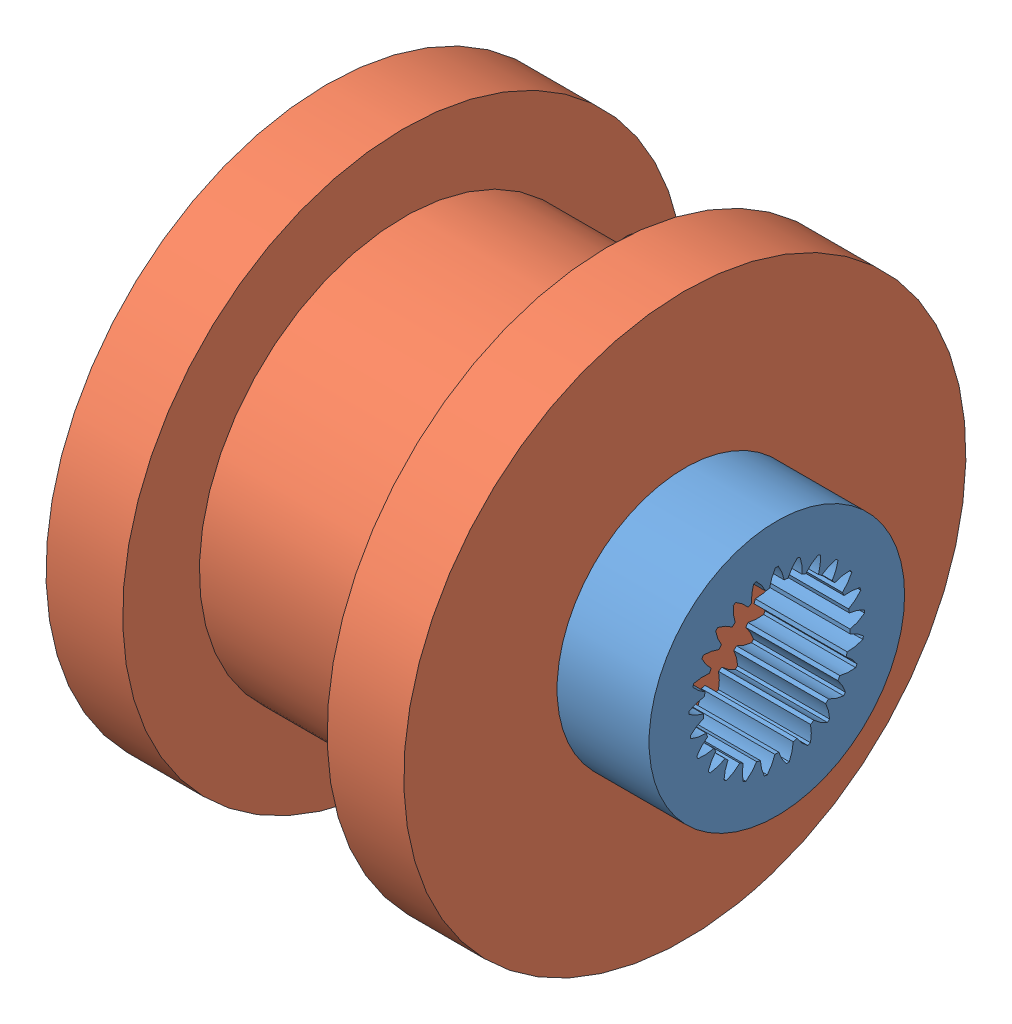
SolidWorks assembly Assem9, configuration Default. Lengths in mm.
Overall size (17.6 26.79 26.79).
2 component instances, 2 part files, 2 mates.
Components (placement in the parent):
- p17-1: p17 [Default] at (6.0098 4.2931 7.103) size (3.6 10 10)
- pully15_1-1: pully15_1 [Default] at (-10.7504 5.4642 6.8141) x (0 -0.968368 -0.249526) z (1 0 0) size (22 22 14)
Mates (geometry in assembly coordinates):
- Concentric1: concentric: cylinder of p17-1 through (3.2496 5.4642 6.8141) axis (1 0 0) radius 5; cylinder of pully15_1-1 through (-10.7504 5.4642 6.8141) axis (1 0 0) radius 1.55
- Coincident1: coincident anti-aligned: plane of p17-1 through (3.2496 5.4642 6.8141) normal (-1 0 0); plane of pully15_1-1 through (3.2496 5.4642 6.8141) normal (1 0 0)
